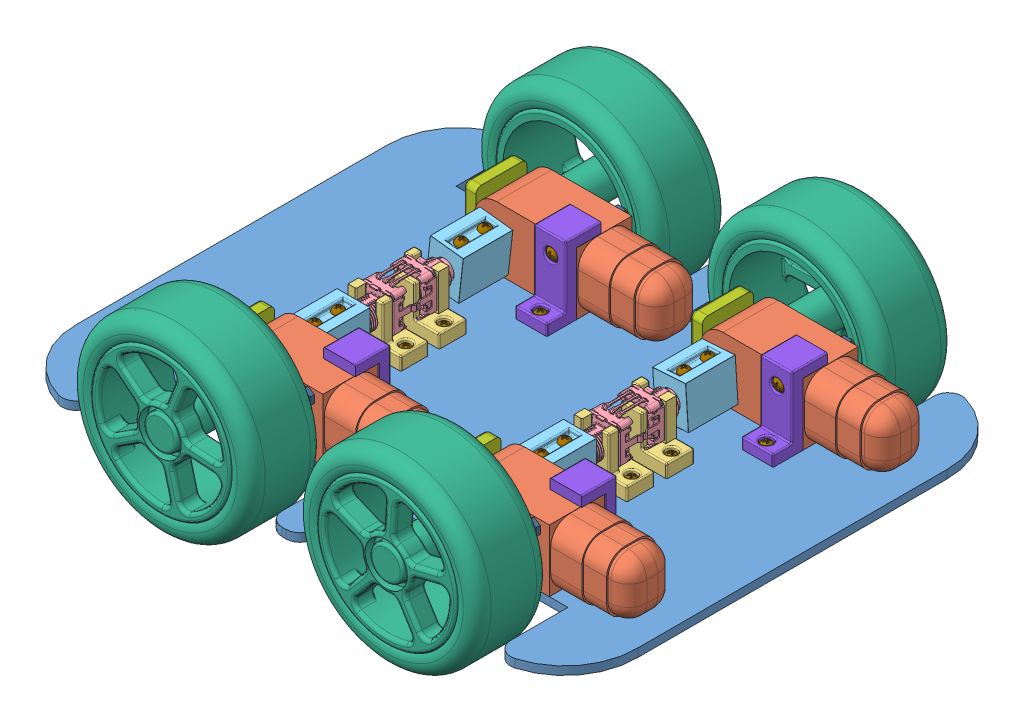
SolidWorks assembly RC Car v2, configuration Default. Lengths in mm.
Overall size (203.21 85.5 173.15).
81 component instances, 10 part files, 181 mates.
Components (placement in the parent):
- Chassis_v1-1: Chassis_v1 [Default] at (-89.4003 13.7937 36.785) size (203.21 3 165.1)
- Motor_v1-3: Motor_v1 [Default] at (-138.9213 39.2937 -19.165) x (1 0 0) z (0 -1 0) size (69.42 36.34 22.5)
- Motor_v1-4: Motor_v1 [Default] at (-138.9213 16.7937 92.735) x (1 0 0) z (0 1 0) size (69.42 36.34 22.5)
- EncoderMount-1: EncoderMount [Default] at (-136.5617 16.7937 48.995) x (0 0 -1) z (1 0 0) size (10 17.94 25.6)
- EncoderMount-2: EncoderMount [Default] at (-123.9617 16.7937 25.075) x (0 0 1) z (-1 0 0) size (10 17.94 25.6)
- Encoder-2: Encoder [Default] at (-130.3117 28.0463 39.685) x (-1 0 0) z (0 0 1) size (14 14.25 28.55)
- Shaft-Encoder-Hub-1: Shaft-Encoder-Hub [Default] at (-130.3117 20.5463 62.235) x (1 0 0) z (0 1 0) size (12 18 15)
- Shaft-Encoder-Hub-2: Shaft-Encoder-Hub [Default] at (-131.1485 20.5879 11.335) x (-0.993756 0.111573 0) z (0.111573 0.993756 0) size (12 18 15)
- Wheel_v2-1: Wheel_v2 [Default] at (-130.3117 28.0463 123.3598) x (0.931323 -0.364194 0) z (0.364194 0.931323 0) size (66 29.12 66)
- Wheel_v2-2: Wheel_v2 [Default] at (-130.3117 28.0411 -49.7897) x (-0.948699 0.31618 0) z (0.31618 0.948699 0) size (66 29.12 66)
- Motor_v1-5: Motor_v1 [Default] at (-56.9152 39.2937 -19.1649) x (1 0 -0.000002) z (0 -1 0) size (69.42 36.34 22.5)
- Motor_v1-6: Motor_v1 [Default] at (-56.9152 16.7937 92.7351) x (1 0 -0.000002) z (0 1 0) size (69.42 36.34 22.5)
- EncoderMount-3: EncoderMount [Default] at (-42.0557 16.7937 24.5751) x (0.000002 0 1) z (-1 0 0.000002) size (10 17.94 25.6)
- EncoderMount-4: EncoderMount [Default] at (-54.6556 16.7937 48.995) x (-0.000002 0 -1) z (1 0 -0.000002) size (10 17.94 25.6)
- Wheel_v2-3: Wheel_v2 [Default] at (-48.4153 28.0437 -49.7896) x (0.960777 -0.277321 -0.000002) z (-0.277321 -0.960777 0.000001) size (66 29.12 66)
- Wheel_v2-4: Wheel_v2 [Default] at (-48.4152 28.0437 123.3598) x (0.997475 -0.071022 -0.000002) z (0.071022 0.997475 0) size (66 29.12 66)
- DCMotorMountRear-1: DCMotorMountRear [Default] at (-56.9153 16.7937 73.2501) x (0 1 0) z (1 0 -0.000002) size (22.45 18.5 11.23)
- DCMotorMountSide-1: DCMotorMountSide [Default] at (-31.4152 43.0337 4.8351) x (0 -1 0) z (0.000002 0 1) size (26.24 11.5 19.6)
- DCMotorMountRear-2: DCMotorMountRear [Default] at (-56.9152 16.7937 -18.1799) x (0 1 0) z (1 0 -0.000002) size (22.45 18.5 11.23)
- DCMotorMountSide-2: DCMotorMountSide [Default] at (-19.4153 43.0337 68.735) x (0 -1 0) z (-0.000002 0 -1) size (26.24 11.5 19.6)
- DCMotorMountSide-3: DCMotorMountSide [Default] at (-113.4213 43.0337 4.835) x (0 -1 0) z (0 0 1) size (26.24 11.5 19.6)
- DCMotorMountRear-3: DCMotorMountRear [Default] at (-138.9213 16.7937 73.25) x (0 1 0) z (1 0 0) size (22.45 18.5 11.23)
- DCMotorMountRear-4: DCMotorMountRear [Default] at (-138.9213 16.7937 -18.18) x (0 1 0) z (1 0 0) size (22.45 18.5 11.23)
- Encoder-3: Encoder [Default] at (-48.3056 28.0463 39.685) x (-1 0 0.000002) z (0.000002 0 1) size (14 14.25 28.55)
- Shaft-Encoder-Hub-3: Shaft-Encoder-Hub [Default] at (-48.3056 20.5463 62.235) x (1 0 -0.000002) z (0 1 0) size (12 18 15)
- Shaft-Encoder-Hub-5: Shaft-Encoder-Hub [Default] at (-47.9011 20.5613 11.3351) x (-0.997648 -0.068548 0.000002) z (-0.068548 0.997648 0) size (12 18 15)
- Encoder-4: Encoder [Default] at (-130.3117 28.0411 34.385) x (1 0 0) z (0 0 -1) size (14 14.25 28.55)
- Encoder-5: Encoder [Default] at (-48.4151 28.0437 33.8851) x (1 0 -0.000002) z (-0.000002 0 -1) size (14 14.25 28.55)
- DCMotorMountSide-4: DCMotorMountSide [Default] at (-101.4213 43.0337 68.735) x (0 -1 0) z (0 0 -1) size (26.24 11.5 19.6)
- round head screw_ai-1: round head screw_ai [CR-RHMS 0.086-56x0.3125x0.3125-N] at (-146.7486 20.7963 -8.93) x (0 -1 0) z (-0.489192 0 0.872176) size (9.64 4.11 4.11)
- round head screw_ai-4: round head screw_ai [CR-RHMS 0.086-64x0.125x0.125-N] at (-130.3431 35.8061 67.235) x (0 -1 0) z (0 0 1) size (4.88 4.11 4.11)
- round head screw_ai-5: round head screw_ai [CR-RHMS 0.086-64x0.125x0.125-N] at (-130.3431 35.8061 58.685) x (0 -1 0) z (0 0 1) size (4.88 4.11 4.11)
- round head screw_ai-8: round head screw_ai [CR-RHMS 0.086-64x0.3125x0.3125-N] at (-120.7217 21.2663 30.075) x (0 -1 0) z (0 0 1) size (9.64 4.11 4.11)
- round head screw_ai-9: round head screw_ai [CR-RHMS 0.086-64x0.3125x0.3125-N] at (-120.7172 21.2663 43.995) x (0 -1 0) z (0 0 1) size (9.64 4.11 4.11)
- round head screw_ai-12: round head screw_ai [CR-RHMS 0.086-64x0.125x0.125-N] at (-129.4146 35.749 14.885) x (-0.111573 -0.993756 0) z (0 0 1) size (4.88 4.11 4.11)
- round head screw_ai-13: round head screw_ai [CR-RHMS 0.086-64x0.125x0.125-N] at (-129.4146 35.749 6.335) x (-0.111573 -0.993756 0) z (0 0 1) size (4.88 4.11 4.11)
- round head screw_ai-16: round head screw_ai [CR-RHMS 0.086-64x0.125x0.125-N] at (-48.9157 35.7874 14.8851) x (0.068548 -0.997648 0) z (0 0 1) size (4.88 4.11 4.11)
- round head screw_ai-17: round head screw_ai [CR-RHMS 0.086-64x0.125x0.125-N] at (-48.9157 35.7874 6.3351) x (0.068548 -0.997648 0) z (0 0 1) size (4.88 4.11 4.11)
- round head screw_ai-22: round head screw_ai [CR-RHMS 0.086-64x0.3125x0.3125-N] at (-38.8157 21.2663 29.5751) x (0 -1 0) z (-0.864943 0 -0.501871) size (9.64 4.11 4.11)
- round head screw_ai-23: round head screw_ai [CR-RHMS 0.086-64x0.3125x0.3125-N] at (-38.8112 21.2663 43.995) x (0 -1 0) z (0.820937 0 -0.571019) size (9.64 4.11 4.11)
- round head screw_ai-24: round head screw_ai [CR-RHMS 0.086-64x0.3125x0.3125-N] at (-57.9001 21.2663 29.5751) x (0 -1 0) z (0.891318 0 -0.453379) size (9.64 4.11 4.11)
- round head screw_ai-25: round head screw_ai [CR-RHMS 0.086-64x0.3125x0.3125-N] at (-57.8956 21.2663 43.9951) x (0 -1 0) z (0.010277 0 -0.999947) size (9.64 4.11 4.11)
- round head screw_ai-26: round head screw_ai [CR-RHMS 0.086-64x0.125x0.125-N] at (-48.3371 35.8061 58.685) x (0 -1 0) z (0 0 1) size (4.88 4.11 4.11)
- round head screw_ai-27: round head screw_ai [CR-RHMS 0.086-64x0.125x0.125-N] at (-48.3371 35.8061 67.235) x (0 -1 0) z (0 0 1) size (4.88 4.11 4.11)
- round head screw_ai-28: round head screw_ai [CR-RHMS 0.086-64x0.3125x0.3125-N] at (-25.1653 20.7963 65.335) x (0 -1 0) z (0 0 1) size (9.64 4.11 4.11)
- round head screw_ai-30: round head screw_ai [CR-RHMS 0.086-64x0.3125x0.3125-N] at (-64.7425 20.7963 82.5001) x (0 -1 0) z (0 0 1) size (9.64 4.11 4.11)
- round head screw_ai-32: round head screw_ai [CR-RHMS 0.086-64x0.3125x0.3125-N] at (-25.6652 20.7963 8.2351) x (0 -1 0) z (0.8593 0 0.511472) size (9.64 4.11 4.11)
- round head screw_ai-34: round head screw_ai [CR-RHMS 0.086-64x0.3125x0.3125-N] at (-139.8017 21.2663 43.995) x (0 -1 0) z (0.862694 0 -0.505726) size (9.64 4.11 4.11)
- round head screw_ai-35: round head screw_ai [CR-RHMS 0.086-64x0.3125x0.3125-N] at (-139.8061 21.2663 30.075) x (0 -1 0) z (0.883954 0 -0.467575) size (9.64 4.11 4.11)
- round head screw_ai-41: round head screw_ai [CR-RHMS 0.086-64x0.3125x0.3125-N] at (-146.7486 20.7963 82.5) x (0 -1 0) z (0 0 1) size (9.64 4.11 4.11)
- round head screw_ai-43: round head screw_ai [CR-RHMS 0.086-64x0.3125x0.3125-N] at (-107.6713 20.7963 8.235) x (0 -1 0) z (0 0 1) size (9.64 4.11 4.11)
- round head screw_ai-45: round head screw_ai [CR-RHMS 0.086-64x0.3125x0.3125-N] at (-64.7424 20.7963 -8.9299) x (0 -1 0) z (0.853062 0 0.52181) size (9.64 4.11 4.11)
- round head screw_ai-49: round head screw_ai [CR-RHMS 0.086-64x0.3125x0.3125-N] at (-107.1713 20.7963 65.335) x (0 -1 0) z (0 0 1) size (9.64 4.11 4.11)
- machine screw nut hex_ai-3: machine screw nut hex_ai [MSHXNUT 0.086-56-S-N] at (-120.7217 12.1173 30.075) x (0.837169 0 0.546944) z (0 -1 0) size (4.78 5.51 1.68)
- machine screw nut hex_ai-4: machine screw nut hex_ai [MSHXNUT 0.086-56-S-N] at (-139.8017 12.1173 43.995) x (0.890955 0 0.454091) z (0 -1 0) size (4.78 5.51 1.68)
- machine screw nut hex_ai-5: machine screw nut hex_ai [MSHXNUT 0.086-56-S-N] at (-120.7172 12.1173 43.995) x (0.837169 0 0.546944) z (0 -1 0) size (4.78 5.51 1.68)
- machine screw nut hex_ai-6: machine screw nut hex_ai [MSHXNUT 0.086-56-S-N] at (-146.7486 13.9311 82.5) x (1 0 0) z (0 1 0) size (4.78 5.51 1.68)
- machine screw nut hex_ai-7: machine screw nut hex_ai [MSHXNUT 0.086-56-S-N] at (-107.1713 12.1173 65.335) x (0.833725 0 0.552179) z (0 -1 0) size (4.78 5.51 1.68)
- machine screw nut hex_ai-8: machine screw nut hex_ai [MSHXNUT 0.086-56-S-N] at (-57.9001 12.1173 29.5751) x (0.837169 0 0.546944) z (0 -1 0) size (4.78 5.51 1.68)
- machine screw nut hex_ai-10: machine screw nut hex_ai [MSHXNUT 0.086-56-S-N] at (-38.8157 12.1173 29.5751) x (0.837169 0 0.546944) z (0 -1 0) size (4.78 5.51 1.68)
- machine screw nut hex_ai-12: machine screw nut hex_ai [MSHXNUT 0.086-56-S-N] at (-57.8956 12.1173 43.9951) x (0.837169 0 0.546944) z (0 -1 0) size (4.78 5.51 1.68)
- machine screw nut hex_ai-13: machine screw nut hex_ai [MSHXNUT 0.086-56-S-N] at (-25.6652 12.1173 8.2351) x (0.837169 0 0.546944) z (0 -1 0) size (4.78 5.51 1.68)
- machine screw nut hex_ai-14: machine screw nut hex_ai [MSHXNUT 0.086-56-S-N] at (-38.8112 12.1173 43.995) x (0.837169 0 0.546944) z (0 -1 0) size (4.78 5.51 1.68)
- machine screw nut hex_ai-15: machine screw nut hex_ai [MSHXNUT 0.086-56-S-N] at (-64.7425 12.1173 82.5001) x (0.837169 0 0.546944) z (0 -1 0) size (4.78 5.51 1.68)
- machine screw nut hex_ai-16: machine screw nut hex_ai [MSHXNUT 0.086-56-S-N] at (-25.1653 12.1173 65.335) x (0.837169 0 0.546944) z (0 -1 0) size (4.78 5.51 1.68)
- machine screw nut hex_ai-17: machine screw nut hex_ai [MSHXNUT 0.086-56-S-N] at (-64.7424 12.1173 -8.9299) x (0.837169 0 0.546944) z (0 -1 0) size (4.78 5.51 1.68)
- machine screw nut hex_ai-19: machine screw nut hex_ai [MSHXNUT 0.086-64-S-N] at (-107.6713 12.1173 8.235) x (0.837169 0 0.546944) z (0 -1 0) size (4.78 5.51 1.68)
- machine screw nut hex_ai-20: machine screw nut hex_ai [MSHXNUT 0.086-56-S-N] at (-146.7486 12.1173 -8.93) x (0.814768 0 0.579788) z (0 -1 0) size (4.78 5.51 1.68)
- machine screw nut hex_ai-21: machine screw nut hex_ai [MSHXNUT 0.086-56-S-N] at (-139.8061 12.1173 30.075) x (0.853088 0 0.521767) z (0 -1 0) size (4.78 5.51 1.68)
- round head screw_ai-55: round head screw_ai [CR-RHMS 0.099-56x1x1-N] at (-25.4152 36.2937 5.3163) x (-0.000002 0 -1) z (-0.335837 -0.94192 0.000001) size (27.33 4.75 4.75)
- round head screw_ai-56: round head screw_ai [CR-RHMS 0.099-56x1x1-N] at (-25.4153 36.2937 68.2538) x (0.000002 0 1) z (-1 0 0.000002) size (27.33 4.75 4.75)
- round head screw_ai-57: round head screw_ai [CR-RHMS 0.099-56x1x1-N] at (-107.4213 36.2937 68.2538) x (0 0 1) z (-1 0 0) size (27.33 4.75 4.75)
- machine screw nut hex_ai-24: machine screw nut hex_ai [MSHXNUT 0.099-56-S-N] at (-107.4213 36.2937 99.1981) x (-0.923728 -0.383049 0) z (0 0 -1) size (4.78 5.51 1.68)
- machine screw nut hex_ai-25: machine screw nut hex_ai [MSHXNUT 0.099-56-S-N] at (-25.4152 36.2937 -25.8056) x (1 0 -0.000002) z (0.000002 0 1) size (4.78 5.51 1.68)
- machine screw nut hex_ai-26: machine screw nut hex_ai [MSHXNUT 0.099-56-S-N] at (-25.4152 36.2937 99.2067) x (-0.923728 -0.383049 0.000002) z (-0.000002 0 -1) size (4.78 5.51 1.68)
- round head screw_ai-58: round head screw_ai [CR-RHMS 0.099-56x1x1-N] at (-107.4213 36.2937 5.3162) x (0 0 -1) z (0.007756 0.99997 0) size (27.33 4.75 4.75)
- machine screw nut hex_ai-28: machine screw nut hex_ai [MSHXNUT 0.099-56-S-N] at (-107.4213 36.2937 -25.7103) size (4.78 5.51 1.68)
- machine screw nut hex_ai-29: machine screw nut hex_ai [MSHXNUT 0.099-56-S-N] at (-25.4152 36.2937 -20.8413) x (0.923728 0.383049 -0.000002) z (-0.000002 0 -1) size (4.78 5.51 1.68)
- machine screw nut hex_ai-30: machine screw nut hex_ai [MSHXNUT 0.099-56-S-N] at (-107.4213 36.2937 -20.8414) x (0.923728 0.383049 0) z (0 0 -1) size (4.78 5.51 1.68)
- machine screw nut hex_ai-31: machine screw nut hex_ai [MSHXNUT 0.099-56-S-N] at (-107.4213 36.2937 94.4114) x (-1 0 0) z (0 0 1) size (4.78 5.51 1.68)
- machine screw nut hex_ai-32: machine screw nut hex_ai [MSHXNUT 0.099-56-S-N] at (-25.4152 36.2937 94.5433) x (-0.999996 0.002881 0.000002) z (0.000002 0 1) size (4.78 5.51 1.68)
Mates (geometry in assembly coordinates):
- Coincident2: coincident anti-aligned: plane of Chassis_v1-1 through (-165.0003 16.7937 -19.765) normal (0 1 0); plane of Motor_v1-3 through (-138.9213 16.7937 0.835) normal (0 -1 0)
- Coincident5: coincident anti-aligned: plane of Chassis_v1-1 through (-165.0003 16.7937 -19.765) normal (0 1 0); plane of Motor_v1-4 through (-138.9213 16.7937 72.735) normal (0 -1 0)
- Parallel3: parallel anti-aligned: plane of Motor_v1-3 through (-130.3117 28.0411 8.235) normal (0 0 1); plane of Motor_v1-4 through (-130.3117 28.0463 65.335) normal (0 0 -1)
- Coincident7: coincident anti-aligned: plane of Chassis_v1-1 through (-165.0003 16.7937 -19.765) normal (0 1 0); plane of EncoderMount-1 through (-123.9617 16.7937 38.995) normal (0 -1 0)
- Parallel4: parallel anti-aligned: plane of Motor_v1-4 through (-138.9213 16.7937 72.735) normal (0 0 -1); plane of EncoderMount-1 through (-123.9617 16.7937 48.995) normal (0 0 1)
- Parallel5: parallel: plane of Chassis_v1-1 through (-165.6003 16.7937 92.735) normal (0 0 1); line of Motor_v1-4 through (-138.9213 28.0437 72.735) axis (1 0 0)
- Coincident11: coincident aligned: plane of Chassis_v1-1 through (-165.6003 16.7937 92.735) normal (0 0 1); plane of Motor_v1-4 through (-138.9213 16.7937 92.735) normal (0 0 1)
- Coincident16: coincident: moEndPointRef_w of Chassis_v1-1; line of Motor_v1-4 through (-130.4213 39.2937 92.735) axis (0 -1 0)
- Coincident19: coincident: moEndPointRef_w of Chassis_v1-1; line of Motor_v1-3 through (-130.4213 16.7937 -19.165) axis (0 1 0)
- Coincident22: coincident anti-aligned: plane of Chassis_v1-1 through (-165.0003 16.7937 -19.765) normal (0 1 0); plane of EncoderMount-2 through (-136.5617 16.7937 35.075) normal (0 -1 0)
- Parallel10: parallel anti-aligned: plane of Motor_v1-3 through (-138.9213 39.2937 0.835) normal (0 0 1); plane of EncoderMount-2 through (-136.5617 16.7937 25.075) normal (0 0 -1)
- Parallel19: parallel anti-aligned: plane of Motor_v1-4 through (-138.9213 16.7937 72.735) normal (0 0 -1); plane of Shaft-Encoder-Hub-1 through (-136.3117 35.5463 71.235) normal (0 0 1)
- Parallel20: parallel anti-aligned: plane of Motor_v1-3 through (-138.9213 39.2937 0.835) normal (0 0 1); plane of Shaft-Encoder-Hub-2 through (-123.5123 34.8248 2.335) normal (0 0 -1)
- Concentric2: concentric aligned: cylinder of Motor_v1-4 through (-130.3117 28.0463 65.335) axis (0 0 1) radius 2.7328; cylinder of Shaft-Encoder-Hub-1 through (-130.3117 28.0463 53.235) axis (0 0 1) radius 3.5
- Concentric5: concentric aligned: cylinder of Motor_v1-3 through (-130.3117 28.0411 8.235) axis (0 0 -1) radius 2.7328; cylinder of Shaft-Encoder-Hub-2 through (-130.3117 28.0411 20.335) axis (0 0 -1) radius 3.5
- Distance4: distance = 1.5 mm anti-aligned: plane of Shaft-Encoder-Hub-2 through (-123.5123 34.8248 2.335) normal (0 0 -1); plane of Motor_v1-3 through (-138.9213 39.2937 0.835) normal (0 0 1)
- Distance5: distance = 1.5 mm anti-aligned: plane of Motor_v1-4 through (-138.9213 16.7937 72.735) normal (0 0 -1); plane of Shaft-Encoder-Hub-1 through (-136.3117 35.5463 71.235) normal (0 0 1)
- Concentric6: concentric anti-aligned: cylinder of Encoder-2 through (-130.3117 28.0463 47.8056) axis (0 0 -1) radius 3; cylinder of Shaft-Encoder-Hub-1 through (-130.3117 28.0463 53.235) axis (0 0 1) radius 3.5
- Distance6: distance = 1 mm anti-aligned: plane of Encoder-2 through (-130.3117 24.0463 52.235) normal (0 0 1); plane of Shaft-Encoder-Hub-1 through (-136.3117 35.5463 53.235) normal (0 0 -1)
- Parallel24: parallel aligned: plane of Chassis_v1-1 through (-165.0003 16.7937 -19.765) normal (0 1 0); plane of Encoder-2 through (-127.9673 32.0463 39.926) normal (0 1 0)
- Coincident46: coincident anti-aligned: plane of EncoderMount-1 through (-123.9617 21.5137 41.185) normal (0 0 1); plane of Encoder-2 through (-126.1117 33.1463 41.185) normal (0 0 -1)
- Parallel25: parallel aligned: plane of EncoderMount-1 through (-136.5617 16.7937 48.995) normal (-1 0 0); plane of Shaft-Encoder-Hub-1 through (-136.3117 35.5463 53.235) normal (-1 0 0)
- Parallel27: parallel aligned: line of EncoderMount-1 through (-130.2617 32.9137 38.995) axis (0 -1 0); line of Shaft-Encoder-Hub-1 through (-130.3117 35.4963 53.235) axis (0 -1 0)
- Concentric8: concentric anti-aligned: cylinder of Motor_v1-4 through (-130.3117 28.0463 65.335) axis (0 0 1) radius 2.7328; cylinder of Wheel_v2-1 through (-130.3117 28.0463 114.0957) axis (0 0 -1) radius 1.675
- Distance11: distance = 1.5 mm anti-aligned: plane of Motor_v1-4 through (-138.9213 16.7937 92.735) normal (0 0 1); plane of Wheel_v2-1 through (-128.7517 27.4362 94.235) normal (0 0 -1)
- Concentric9: concentric anti-aligned: cylinder of Motor_v1-3 through (-130.3117 28.0411 8.235) axis (0 0 -1) radius 2.7328; circle of Wheel_v2-2
- Distance13: distance = 1.5 mm anti-aligned: plane of Wheel_v2-2 through (-131.9007 28.5707 -20.665) normal (0 0 1); plane of Motor_v1-3 through (-138.9213 39.2937 -19.165) normal (0 0 -1)
- Coincident66: coincident anti-aligned: plane of Chassis_v1-1 through (-165.0003 16.7937 -19.765) normal (0 1 0); plane of Motor_v1-6 through (-56.9153 16.7937 72.7351) normal (0 -1 0)
- Coincident69: coincident anti-aligned: plane of Chassis_v1-1 through (-165.0003 16.7937 -19.765) normal (0 1 0); plane of Motor_v1-5 through (-56.9152 16.7937 0.8351) normal (0 -1 0)
- Coincident70: coincident aligned: plane of Chassis_v1-1 through (-13.2003 16.7937 -19.165) normal (-0.000002 0 -1); plane of Motor_v1-5 through (-56.9152 39.2937 -19.1649) normal (-0.000002 0 -1)
- Coincident71: coincident: moEndPointRef_w of Chassis_v1-1; line of Motor_v1-5 through (-48.4152 16.7937 -19.1649) axis (0 1 0)
- Concentric10: concentric anti-aligned: cylinder of Motor_v1-5 through (-48.4152 28.0437 8.2351) axis (-0.000002 0 -1) radius 2.6721; cylinder of Wheel_v2-3 through (-48.4153 28.0437 -40.5255) axis (0.000002 0 1) radius 1.675
- Distance14: distance = 1.5 mm anti-aligned: plane of Motor_v1-5 through (-56.9152 39.2937 -19.1649) normal (-0.000002 0 -1); plane of Wheel_v2-3 through (-46.8059 27.5792 -20.6649) normal (0.000002 0 1)
- Concentric11: concentric anti-aligned: cylinder of Motor_v1-6 through (-48.4153 28.0437 65.335) axis (0.000002 0 1) radius 2.6721; cylinder of Wheel_v2-4 through (-48.4152 28.0437 114.0957) axis (-0.000002 0 -1) radius 1.675
- Distance15: distance = 1.5 mm anti-aligned: plane of Motor_v1-6 through (-56.9152 16.7937 92.7351) normal (0.000002 0 1); plane of Wheel_v2-4 through (-46.7445 27.9247 94.235) normal (-0.000002 0 -1)
- Parallel29: parallel anti-aligned: plane of Motor_v1-6 through (-56.9153 16.7937 72.7351) normal (-0.000002 0 -1); plane of EncoderMount-4 through (-42.0556 16.7937 48.995) normal (0.000002 0 1)
- Parallel30: parallel anti-aligned: plane of Motor_v1-5 through (-56.9152 39.2937 0.8351) normal (0.000002 0 1); plane of EncoderMount-3 through (-54.6557 16.7937 24.5751) normal (-0.000002 0 -1)
- Coincident81: coincident aligned: line of EncoderMount-1 through (-142.5617 21.5137 39.495) axis (0 0 1); line of EncoderMount-2 through (-142.5617 21.5137 25.575) axis (0 0 1)
- Coincident82: coincident aligned: line of EncoderMount-3 through (-60.6557 21.5137 25.0751) axis (0.000002 0 1); line of EncoderMount-4 through (-60.6556 21.5137 39.4951) axis (0.000002 0 1)
- Coincident83: coincident anti-aligned: plane of Chassis_v1-1 through (-165.0003 16.7937 -19.765) normal (0 1 0); plane of DCMotorMountRear-1 through (-56.9152 16.7937 91.7501) normal (0 -1 0)
- Coincident86: coincident anti-aligned: plane of Motor_v1-6 through (-56.9153 16.7937 72.7351) normal (-1 0 0.000002); plane of DCMotorMountRear-1 through (-56.9152 39.2437 91.7501) normal (1 0 -0.000002)
- Coincident87: coincident anti-aligned: plane of Motor_v1-6 through (-62.0452 25.4787 84.1501) normal (0.000002 0 1); plane of DCMotorMountRear-1 through (-61.4152 24.7937 84.1501) normal (-0.000002 0 -1)
- Coincident88: coincident anti-aligned: plane of Chassis_v1-1 through (-165.0003 16.7937 -19.765) normal (0 1 0); plane of DCMotorMountSide-1 through (-19.9152 16.7937 0.835) normal (0 -1 0)
- Coincident92: coincident anti-aligned: plane of Motor_v1-5 through (-56.9152 39.2937 0.8351) normal (0.000002 0 1); plane of DCMotorMountSide-1 through (-19.9152 39.3937 0.835) normal (-0.000002 0 -1)
- Coincident93: coincident anti-aligned: plane of Chassis_v1-1 through (-165.0003 16.7937 -19.765) normal (0 1 0); plane of DCMotorMountRear-2 through (-56.9152 16.7937 0.3201) normal (0 -1 0)
- Coincident94: coincident anti-aligned: plane of Motor_v1-5 through (-56.9152 39.2937 0.8351) normal (-1 0 0.000002); plane of DCMotorMountRear-2 through (-56.9152 39.2437 0.3201) normal (1 0 -0.000002)
- Coincident95: coincident anti-aligned: plane of Motor_v1-5 through (-62.0452 30.6087 -10.5799) normal (-0.000002 0 -1); plane of DCMotorMountRear-2 through (-61.4152 31.2437 -10.5799) normal (0.000002 0 1)
- Coincident96: coincident anti-aligned: plane of Chassis_v1-1 through (-165.0003 16.7937 -19.765) normal (0 1 0); plane of DCMotorMountSide-2 through (-30.9153 16.7937 72.735) normal (0 -1 0)
- Coincident99: coincident anti-aligned: plane of Chassis_v1-1 through (-165.0003 16.7937 -19.765) normal (0 1 0); plane of DCMotorMountSide-3 through (-101.9213 16.7937 0.835) normal (0 -1 0)
- Coincident100: coincident anti-aligned: plane of Motor_v1-3 through (-138.9213 39.2937 0.835) normal (0 0 1); plane of DCMotorMountSide-3 through (-101.9213 39.3937 0.835) normal (0 0 -1)
- Coincident101: coincident anti-aligned: plane of Chassis_v1-1 through (-165.0003 16.7937 -19.765) normal (0 1 0); plane of DCMotorMountRear-3 through (-138.9213 16.7937 91.75) normal (0 -1 0)
- Coincident102: coincident anti-aligned: plane of Motor_v1-4 through (-138.9213 16.7937 72.735) normal (-1 0 0); plane of DCMotorMountRear-3 through (-138.9213 39.2437 91.75) normal (1 0 0)
- Coincident103: coincident anti-aligned: plane of Motor_v1-4 through (-144.0513 25.4787 84.15) normal (0 0 1); plane of DCMotorMountRear-3 through (-143.4213 24.7937 84.15) normal (0 0 -1)
- Coincident104: coincident anti-aligned: plane of Chassis_v1-1 through (-165.0003 16.7937 -19.765) normal (0 1 0); plane of DCMotorMountRear-4 through (-138.9213 16.7937 0.32) normal (0 -1 0)
- Coincident105: coincident anti-aligned: plane of Motor_v1-3 through (-138.9213 39.2937 0.835) normal (-1 0 0); plane of DCMotorMountRear-4 through (-138.9213 39.2437 0.32) normal (1 0 0)
- Coincident106: coincident anti-aligned: plane of Motor_v1-3 through (-144.0513 30.6087 -10.58) normal (0 0 -1); plane of DCMotorMountRear-4 through (-143.4213 31.2437 -10.58) normal (0 0 1)
- Distance16: distance = 1.5 mm anti-aligned: plane of Motor_v1-6 through (-56.9153 16.7937 72.7351) normal (-0.000002 0 -1); plane of Shaft-Encoder-Hub-3 through (-54.3056 35.5463 71.235) normal (0.000002 0 1)
- Concentric18: concentric aligned: cylinder of Motor_v1-6 through (-48.3056 28.0463 65.335) axis (0.000002 0 1) radius 2.7328; circle of Shaft-Encoder-Hub-3
- Concentric19: concentric anti-aligned: cylinder of Encoder-3 through (-48.3056 28.0463 47.8056) axis (-0.000002 0 -1) radius 3; cylinder of Shaft-Encoder-Hub-3 through (-48.3056 28.0463 53.235) axis (0.000002 0 1) radius 3.5
- Distance17: distance = 1 mm anti-aligned: plane of Encoder-3 through (-48.3056 24.0463 52.235) normal (0.000002 0 1); plane of Shaft-Encoder-Hub-3 through (-54.3056 35.5463 53.235) normal (-0.000002 0 -1)
- Coincident110: coincident anti-aligned: plane of Chassis_v1-1 through (-165.0003 16.7937 -19.765) normal (0 1 0); plane of EncoderMount-3 through (-54.6557 16.7937 34.5751) normal (0 -1 0)
- Coincident112: coincident anti-aligned: plane of Chassis_v1-1 through (-165.0003 16.7937 -19.765) normal (0 1 0); plane of EncoderMount-4 through (-42.0557 16.7937 38.995) normal (0 -1 0)
- Coincident113: coincident anti-aligned: plane of EncoderMount-4 through (-42.0556 21.5137 41.185) normal (0.000002 0 1); plane of Encoder-3 through (-44.1056 33.1463 41.185) normal (-0.000002 0 -1)
- Coincident116: coincident anti-aligned: plane of EncoderMount-4 through (-44.4556 16.7937 41.855) normal (1 0 -0.000002); plane of Encoder-3 through (-44.4556 22.1463 39.685) normal (-1 0 0.000002)
- Distance20: distance = 1.5 mm anti-aligned: plane of Motor_v1-5 through (-56.9152 39.2937 0.8351) normal (0.000002 0 1); plane of Shaft-Encoder-Hub-5 through (-42.9434 35.9373 2.3351) normal (-0.000002 0 -1)
- Concentric20: concentric aligned: cylinder of Motor_v1-5 through (-48.4152 28.0437 8.2351) axis (-0.000002 0 -1) radius 2.6721; cylinder of Shaft-Encoder-Hub-5 through (-48.4151 28.0437 20.3351) axis (-0.000002 0 -1) radius 3.5
- Coincident118: coincident anti-aligned: plane of EncoderMount-1 through (-134.1617 16.7937 41.855) normal (-1 0 0); plane of Encoder-2 through (-134.1617 22.1463 39.685) normal (1 0 0)
- Coincident119: coincident anti-aligned: plane of Motor_v1-6 through (-56.9153 16.7937 72.7351) normal (-0.000002 0 -1); plane of DCMotorMountSide-2 through (-30.9153 39.3937 72.735) normal (0.000002 0 1)
- Concentric21: concentric anti-aligned: cylinder of Shaft-Encoder-Hub-2 through (-130.3117 28.0411 20.335) axis (0 0 -1) radius 3.5; cylinder of Encoder-4 through (-130.3117 28.0411 26.2645) axis (0 0 1) radius 3
- Distance21: distance = 1.5 mm anti-aligned: plane of Encoder-4 through (-130.3117 24.0411 21.835) normal (0 0 -1); plane of Shaft-Encoder-Hub-2 through (-123.5123 34.8248 20.335) normal (0 0 1)
- Coincident122: coincident anti-aligned: plane of EncoderMount-2 through (-136.5617 21.5137 32.885) normal (0 0 -1); plane of Encoder-4 through (-134.5117 33.1411 32.885) normal (0 0 1)
- Parallel44: parallel anti-aligned: plane of EncoderMount-2 through (-126.3617 16.7937 32.215) normal (1 0 0); plane of Encoder-4 through (-126.4617 22.1411 34.385) normal (-1 0 0)
- Concentric22: concentric anti-aligned: cylinder of Shaft-Encoder-Hub-5 through (-48.4151 28.0437 20.3351) axis (-0.000002 0 -1) radius 3.5; cylinder of Encoder-5 through (-48.4151 28.0437 25.7646) axis (0.000002 0 1) radius 3
- Distance22: distance = 1 mm anti-aligned: plane of Encoder-5 through (-48.4151 24.0437 21.3351) normal (-0.000002 0 -1); plane of Shaft-Encoder-Hub-5 through (-42.9434 35.9373 20.3351) normal (0.000002 0 1)
- Coincident127: coincident anti-aligned: plane of EncoderMount-3 through (-54.6557 21.5137 32.3851) normal (-0.000002 0 -1); plane of Encoder-5 through (-52.6151 33.1437 32.3851) normal (0.000002 0 1)
- Parallel47: parallel anti-aligned: plane of EncoderMount-3 through (-52.2557 16.7937 31.7151) normal (-1 0 0.000002); plane of Encoder-5 through (-52.2651 22.1437 33.8851) normal (1 0 -0.000002)
- Coincident132: coincident anti-aligned: plane of Chassis_v1-1 through (-165.0003 16.7937 -19.765) normal (0 1 0); plane of DCMotorMountSide-4 through (-112.9213 16.7937 72.735) normal (0 -1 0)
- Coincident133: coincident anti-aligned: plane of Motor_v1-4 through (-138.9213 16.7937 72.735) normal (0 0 -1); plane of DCMotorMountSide-4 through (-112.9213 39.3937 72.735) normal (0 0 1)
- Concentric32: concentric aligned: cylinder of DCMotorMountRear-4 through (-146.7486 16.7437 -8.93) axis (0 1 0) radius 1.15; cylinder of round head screw_ai-1 through (-146.7486 20.7963 -8.93) axis (0 1 0) radius 1.0922
- Coincident143: coincident anti-aligned: circle of DCMotorMountRear-4; plane of round head screw_ai-1 through (-145.796 19.0437 -8.3957) normal (0 -1 0)
- Concentric33: concentric aligned: cylinder of Shaft-Encoder-Hub-1 through (-130.3431 31.0535 67.235) axis (0 1 0) radius 1.05; cylinder of round head screw_ai-4 through (-130.3431 35.8061 67.235) axis (0 1 0) radius 1.0922
- Coincident145: coincident anti-aligned: plane of Shaft-Encoder-Hub-1 through (-130.3117 34.0535 62.235) normal (0 1 0); plane of round head screw_ai-4 through (-129.2509 34.0535 67.235) normal (0 -1 0)
- Concentric34: concentric aligned: cylinder of Shaft-Encoder-Hub-1 through (-130.3431 31.0535 58.685) axis (0 1 0) radius 1.05; cylinder of round head screw_ai-5 through (-130.3431 35.8061 58.685) axis (0 1 0) radius 1.0922
- Coincident146: coincident anti-aligned: plane of Shaft-Encoder-Hub-1 through (-130.3117 34.0535 62.235) normal (0 1 0); plane of round head screw_ai-5 through (-129.2509 34.0535 58.685) normal (0 -1 0)
- Concentric37: concentric anti-aligned: cylinder of EncoderMount-2 through (-120.7217 19.7937 30.075) axis (0 -1 0) radius 1.25; cylinder of round head screw_ai-8 through (-120.7217 21.2663 30.075) axis (0 1 0) radius 1.0922
- Coincident149: coincident anti-aligned: plane of EncoderMount-2 through (-120.7217 19.5137 30.075) normal (0 1 0); plane of round head screw_ai-8 through (-119.6295 19.5137 30.075) normal (0 -1 0)
- Concentric38: concentric anti-aligned: cylinder of EncoderMount-1 through (-120.7172 19.7937 43.995) axis (0 -1 0) radius 1.25; cylinder of round head screw_ai-9 through (-120.7172 21.2663 43.995) axis (0 1 0) radius 1.0922
- Coincident150: coincident anti-aligned: plane of EncoderMount-1 through (-120.7172 19.5137 43.995) normal (0 1 0); plane of round head screw_ai-9 through (-119.625 19.5137 43.995) normal (0 -1 0)
- Concentric39: concentric aligned: cylinder of Shaft-Encoder-Hub-2 through (-129.9448 31.0261 14.885) axis (0.111573 0.993756 0) radius 1.05; cylinder of round head screw_ai-12 through (-129.4146 35.749 14.885) axis (0.111573 0.993756 0) radius 1.0922
- Coincident151: coincident anti-aligned: plane of Shaft-Encoder-Hub-2 through (-129.6414 34.0108 11.335) normal (0.111573 0.993756 0); plane of round head screw_ai-12 through (-128.5248 33.8855 14.885) normal (-0.111573 -0.993756 0)
- Concentric40: concentric aligned: cylinder of Shaft-Encoder-Hub-2 through (-129.9448 31.0261 6.335) axis (0.111573 0.993756 0) radius 1.05; cylinder of round head screw_ai-13 through (-129.4146 35.749 6.335) axis (0.111573 0.993756 0) radius 1.0922
- Coincident152: coincident anti-aligned: plane of Shaft-Encoder-Hub-2 through (-129.6414 34.0108 11.335) normal (0.111573 0.993756 0); plane of round head screw_ai-13 through (-128.5248 33.8855 6.335) normal (-0.111573 -0.993756 0)
- Concentric43: concentric aligned: cylinder of Shaft-Encoder-Hub-5 through (-48.5899 31.046 14.8851) axis (-0.068548 0.997648 0) radius 1.05; cylinder of round head screw_ai-16 through (-48.9157 35.7874 14.8851) axis (-0.068548 0.997648 0) radius 1.0922
- Coincident154: coincident anti-aligned: plane of Shaft-Encoder-Hub-5 through (-48.827 34.0368 11.3351) normal (-0.068548 0.997648 0); plane of round head screw_ai-16 through (-47.7059 34.1138 14.8851) normal (0.068548 -0.997648 0)
- Concentric44: concentric aligned: cylinder of Shaft-Encoder-Hub-5 through (-48.5899 31.046 6.3351) axis (-0.068548 0.997648 0) radius 1.05; cylinder of round head screw_ai-17 through (-48.9157 35.7874 6.3351) axis (-0.068548 0.997648 0) radius 1.0922
- Coincident155: coincident anti-aligned: plane of Shaft-Encoder-Hub-5 through (-48.827 34.0368 11.3351) normal (-0.068548 0.997648 0); plane of round head screw_ai-17 through (-47.7059 34.1138 6.3351) normal (0.068548 -0.997648 0)
- Concentric45: concentric anti-aligned: cylinder of EncoderMount-3 through (-38.8157 19.7937 29.5751) axis (0 -1 0) radius 1.25; cylinder of round head screw_ai-22 through (-38.8157 21.2663 29.5751) axis (0 1 0) radius 1.0922
- Coincident156: coincident anti-aligned: plane of EncoderMount-3 through (-38.8157 19.5137 29.5751) normal (0 1 0); plane of round head screw_ai-22 through (-39.3638 19.5137 30.5198) normal (0 -1 0)
- Concentric46: concentric anti-aligned: cylinder of EncoderMount-4 through (-38.8112 19.7937 43.995) axis (0 -1 0) radius 1.25; cylinder of round head screw_ai-23 through (-38.8112 21.2663 43.995) axis (0 1 0) radius 1.0922
- Coincident157: coincident anti-aligned: plane of EncoderMount-4 through (-38.8112 19.5137 43.995) normal (0 1 0); plane of round head screw_ai-23 through (-39.4349 19.5137 43.0984) normal (0 -1 0)
- Concentric47: concentric anti-aligned: cylinder of EncoderMount-3 through (-57.9001 19.7937 29.5751) axis (0 -1 0) radius 1.25; cylinder of round head screw_ai-24 through (-57.9001 21.2663 29.5751) axis (0 1 0) radius 1.0922
- Coincident158: coincident anti-aligned: plane of EncoderMount-3 through (-57.9001 19.5137 29.5751) normal (0 1 0); plane of round head screw_ai-24 through (-58.3953 19.5137 28.6016) normal (0 -1 0)
- Concentric48: concentric anti-aligned: cylinder of EncoderMount-4 through (-57.8956 19.7937 43.9951) axis (0 -1 0) radius 1.25; cylinder of round head screw_ai-25 through (-57.8956 21.2663 43.9951) axis (0 1 0) radius 1.0922
- Concentric49: concentric aligned: cylinder of Shaft-Encoder-Hub-3 through (-48.3371 31.0535 58.685) axis (0 1 0) radius 1.05; cylinder of round head screw_ai-26 through (-48.3371 35.8061 58.685) axis (0 1 0) radius 1.0922
- Coincident159: coincident anti-aligned: plane of Shaft-Encoder-Hub-3 through (-48.3056 34.0535 62.235) normal (0 1 0); plane of round head screw_ai-26 through (-47.2449 34.0535 58.685) normal (0 -1 0)
- Concentric50: concentric aligned: cylinder of Shaft-Encoder-Hub-3 through (-48.3371 31.0535 67.235) axis (0 1 0) radius 1.05; cylinder of round head screw_ai-27 through (-48.3371 35.8061 67.235) axis (0 1 0) radius 1.0922
- Coincident160: coincident anti-aligned: plane of Shaft-Encoder-Hub-3 through (-48.3056 34.0535 62.235) normal (0 1 0); plane of round head screw_ai-27 through (-47.2449 34.0535 67.235) normal (0 -1 0)
- Concentric51: concentric aligned: cylinder of DCMotorMountSide-2 through (-25.1653 16.5437 65.335) axis (0 1 0) radius 1.15; cylinder of round head screw_ai-28 through (-25.1653 20.7963 65.335) axis (0 1 0) radius 1.0922
- Coincident161: coincident anti-aligned: plane of DCMotorMountSide-2 through (-25.1653 19.0437 65.335) normal (0 1 0); plane of round head screw_ai-28 through (-24.0731 19.0437 65.335) normal (0 -1 0)
- Concentric53: concentric aligned: cylinder of DCMotorMountRear-1 through (-64.7425 16.7437 82.5001) axis (0 1 0) radius 1.15; cylinder of round head screw_ai-30 through (-64.7425 20.7963 82.5001) axis (0 1 0) radius 1.0922
- Coincident163: coincident anti-aligned: plane of DCMotorMountRear-1 through (-64.7425 19.0437 82.5001) normal (0 1 0); plane of round head screw_ai-30 through (-63.6503 19.0437 82.5001) normal (0 -1 0)
- Concentric55: concentric aligned: cylinder of DCMotorMountSide-1 through (-25.6652 16.5437 8.2351) axis (0 1 0) radius 1.15; cylinder of round head screw_ai-32 through (-25.6652 20.7963 8.2351) axis (0 1 0) radius 1.0922
- Coincident164: coincident anti-aligned: plane of DCMotorMountSide-1 through (-25.6652 19.0437 8.2351) normal (0 1 0); plane of round head screw_ai-32 through (-25.1065 19.0437 7.2965) normal (0 -1 0)
- Concentric57: concentric anti-aligned: cylinder of EncoderMount-1 through (-139.8017 19.7937 43.995) axis (0 -1 0) radius 1.25; cylinder of round head screw_ai-34 through (-139.8017 21.2663 43.995) axis (0 1 0) radius 1.0922
- Coincident166: coincident anti-aligned: plane of EncoderMount-1 through (-139.8017 19.5137 43.995) normal (0 1 0); plane of round head screw_ai-34 through (-140.354 19.5137 43.0528) normal (0 -1 0)
- Concentric58: concentric anti-aligned: cylinder of EncoderMount-2 through (-139.8061 19.7937 30.075) axis (0 -1 0) radius 1.25; cylinder of round head screw_ai-35 through (-139.8061 21.2663 30.075) axis (0 1 0) radius 1.0922
- Concentric59: concentric aligned: cylinder of DCMotorMountRear-3 through (-146.7486 16.7437 82.5) axis (0 1 0) radius 1.15; cylinder of round head screw_ai-41 through (-146.7486 20.7963 82.5) axis (0 1 0) radius 1.0922
- Coincident170: coincident anti-aligned: plane of DCMotorMountRear-3 through (-146.7486 19.0437 82.5) normal (0 1 0); plane of round head screw_ai-41 through (-145.6564 19.0437 82.5) normal (0 -1 0)
- Concentric61: concentric aligned: cylinder of DCMotorMountSide-3 through (-107.6713 16.5437 8.235) axis (0 1 0) radius 1.15; cylinder of round head screw_ai-43 through (-107.6713 20.7963 8.235) axis (0 1 0) radius 1.0922
- Coincident172: coincident anti-aligned: plane of DCMotorMountSide-3 through (-107.6713 19.0437 8.235) normal (0 1 0); plane of round head screw_ai-43 through (-106.5791 19.0437 8.235) normal (0 -1 0)
- Concentric62: concentric aligned: cylinder of DCMotorMountRear-2 through (-64.7424 16.7437 -8.9299) axis (0 1 0) radius 1.15; cylinder of round head screw_ai-45 through (-64.7424 20.7963 -8.9299) axis (0 1 0) radius 1.0922
- Coincident174: coincident anti-aligned: plane of DCMotorMountRear-2 through (-64.7424 19.0437 -8.9299) normal (0 1 0); plane of round head screw_ai-45 through (-64.1725 19.0437 -9.8616) normal (0 -1 0)
- Concentric68: concentric aligned: cylinder of DCMotorMountSide-4 through (-107.1713 16.5437 65.335) axis (0 1 0) radius 1.15; cylinder of round head screw_ai-49 through (-107.1713 20.7963 65.335) axis (0 1 0) radius 1.0922
- Coincident178: coincident anti-aligned: plane of DCMotorMountSide-4 through (-107.1713 19.0437 65.335) normal (0 1 0); plane of round head screw_ai-49 through (-106.0791 19.0437 65.335) normal (0 -1 0)
- Concentric72: concentric anti-aligned: cylinder of round head screw_ai-8 through (-120.7217 21.2663 30.075) axis (0 1 0) radius 1.0922; cylinder of machine screw nut hex_ai-3 through (-120.7217 37.1548 30.075) axis (0 -1 0) radius 1.0922
- Concentric73: concentric anti-aligned: cylinder of round head screw_ai-34 through (-139.8017 21.2663 43.995) axis (0 1 0) radius 1.0922; cylinder of machine screw nut hex_ai-4 through (-139.8017 37.1548 43.995) axis (0 -1 0) radius 1.0922
- Concentric74: concentric anti-aligned: cylinder of round head screw_ai-9 through (-120.7172 21.2663 43.995) axis (0 1 0) radius 1.0922; cylinder of machine screw nut hex_ai-5 through (-120.7172 37.1548 43.995) axis (0 -1 0) radius 1.0922
- Concentric75: concentric aligned: cylinder of round head screw_ai-41 through (-146.7486 20.7963 82.5) axis (0 1 0) radius 1.0922; cylinder of machine screw nut hex_ai-6 through (-146.7486 -11.1064 82.5) axis (0 1 0) radius 1.0922
- Concentric76: concentric anti-aligned: cylinder of round head screw_ai-49 through (-107.1713 20.7963 65.335) axis (0 1 0) radius 1.0922; cylinder of machine screw nut hex_ai-7 through (-107.1713 37.1548 65.335) axis (0 -1 0) radius 1.0922
- Concentric77: concentric anti-aligned: cylinder of round head screw_ai-24 through (-57.9001 21.2663 29.5751) axis (0 1 0) radius 1.0922; cylinder of machine screw nut hex_ai-8 through (-57.9001 37.1548 29.5751) axis (0 -1 0) radius 1.0922
- Concentric78: concentric anti-aligned: cylinder of round head screw_ai-22 through (-38.8157 21.2663 29.5751) axis (0 1 0) radius 1.0922; cylinder of machine screw nut hex_ai-10 through (-38.8157 37.1548 29.5751) axis (0 -1 0) radius 1.0922
- Concentric79: concentric anti-aligned: cylinder of round head screw_ai-25 through (-57.8956 21.2663 43.9951) axis (0 1 0) radius 1.0922; cylinder of machine screw nut hex_ai-12 through (-57.8956 37.1548 43.9951) axis (0 -1 0) radius 1.0922
- Concentric80: concentric anti-aligned: cylinder of round head screw_ai-32 through (-25.6652 20.7963 8.2351) axis (0 1 0) radius 1.0922; cylinder of machine screw nut hex_ai-13 through (-25.6652 37.1548 8.2351) axis (0 -1 0) radius 1.0922
- Concentric81: concentric anti-aligned: cylinder of round head screw_ai-23 through (-38.8112 21.2663 43.995) axis (0 1 0) radius 1.0922; cylinder of machine screw nut hex_ai-14 through (-38.8112 37.1548 43.995) axis (0 -1 0) radius 1.0922
- Concentric82: concentric anti-aligned: cylinder of round head screw_ai-30 through (-64.7425 20.7963 82.5001) axis (0 1 0) radius 1.0922; cylinder of machine screw nut hex_ai-15 through (-64.7425 37.1548 82.5001) axis (0 -1 0) radius 1.0922
- Concentric83: concentric anti-aligned: cylinder of round head screw_ai-28 through (-25.1653 20.7963 65.335) axis (0 1 0) radius 1.0922; cylinder of machine screw nut hex_ai-16 through (-25.1653 37.1548 65.335) axis (0 -1 0) radius 1.0922
- Concentric84: concentric anti-aligned: cylinder of round head screw_ai-45 through (-64.7424 20.7963 -8.9299) axis (0 1 0) radius 1.0922; cylinder of machine screw nut hex_ai-17 through (-64.7424 37.1548 -8.9299) axis (0 -1 0) radius 1.0922
- Concentric85: concentric anti-aligned: cylinder of round head screw_ai-43 through (-107.6713 20.7963 8.235) axis (0 1 0) radius 1.0922; cylinder of machine screw nut hex_ai-19 through (-107.6713 37.1548 8.235) axis (0 -1 0) radius 1.0922
- Concentric86: concentric anti-aligned: cylinder of round head screw_ai-1 through (-146.7486 20.7963 -8.93) axis (0 1 0) radius 1.0922; cylinder of machine screw nut hex_ai-20 through (-146.7486 37.1548 -8.93) axis (0 -1 0) radius 1.0922
- Concentric87: concentric anti-aligned: cylinder of round head screw_ai-35 through (-139.8061 21.2663 30.075) axis (0 1 0) radius 1.0922; cylinder of machine screw nut hex_ai-21 through (-139.8061 37.1548 30.075) axis (0 -1 0) radius 1.0922
- Concentric103: concentric aligned: cylinder of round head screw_ai-57 through (-107.4213 36.2937 68.2538) axis (0 0 -1) radius 1.2573; cylinder of machine screw nut hex_ai-24 through (-107.4213 36.2937 124.2356) axis (0 0 -1) radius 1.2573
- Concentric104: concentric aligned: cylinder of round head screw_ai-55 through (-25.4152 36.2937 5.3163) axis (0.000002 0 1) radius 1.2573; cylinder of machine screw nut hex_ai-25 through (-25.4153 36.2937 -50.8431) axis (0.000002 0 1) radius 1.2573
- Concentric105: concentric aligned: cylinder of round head screw_ai-56 through (-25.4153 36.2937 68.2538) axis (-0.000002 0 -1) radius 1.2573; cylinder of machine screw nut hex_ai-26 through (-25.4152 36.2937 124.2442) axis (-0.000002 0 -1) radius 1.2573
- Concentric108: concentric aligned: cylinder of round head screw_ai-58 through (-107.4213 36.2937 5.3162) axis (0 0 1) radius 1.2573; cylinder of machine screw nut hex_ai-28 through (-107.4213 36.2937 -50.7478) axis (0 0 1) radius 1.2573
- Coincident1892: coincident: moEndPointRef_w of Chassis_v1-1; line of Motor_v1-6 through (-48.4152 39.2937 92.735) axis (0 -1 0)
- Concentric117: concentric anti-aligned: cylinder of Motor_v1-5 through (-25.4152 36.2937 2.6751) axis (-0.000002 0 -1) radius 1.5; cylinder of DCMotorMountSide-1 through (-25.4152 36.2937 0.3351) axis (0.000002 0 1) radius 1.5
- Concentric118: concentric anti-aligned: cylinder of Motor_v1-5 through (-25.4152 36.2937 2.6751) axis (-0.000002 0 -1) radius 1.5; cylinder of round head screw_ai-55 through (-25.4152 36.2937 5.3163) axis (0.000002 0 1) radius 1.2573
- Coincident1901: coincident anti-aligned: plane of DCMotorMountSide-1 through (-25.4152 36.2937 3.3351) normal (0.000002 0 1); plane of round head screw_ai-55 through (-24.2309 35.8714 3.3351) normal (-0.000002 0 -1)
- Concentric119: concentric anti-aligned: cylinder of Motor_v1-3 through (-107.4213 36.2937 2.675) axis (0 0 -1) radius 1.5; cylinder of DCMotorMountSide-3 through (-107.4213 36.2937 0.335) axis (0 0 1) radius 1.5
- Concentric120: concentric anti-aligned: cylinder of Motor_v1-3 through (-107.4213 36.2937 2.675) axis (0 0 -1) radius 1.5; cylinder of round head screw_ai-58 through (-107.4213 36.2937 5.3162) axis (0 0 1) radius 1.2573
- Coincident1902: coincident anti-aligned: plane of DCMotorMountSide-3 through (-107.4213 36.2937 3.335) normal (0 0 1); plane of round head screw_ai-58 through (-108.6786 36.3034 3.335) normal (0 0 -1)
- Concentric121: concentric anti-aligned: cylinder of Motor_v1-4 through (-107.4213 36.2937 70.895) axis (0 0 1) radius 1.5; cylinder of DCMotorMountSide-4 through (-107.4213 36.2937 73.235) axis (0 0 -1) radius 1.5
- Concentric122: concentric anti-aligned: cylinder of Motor_v1-4 through (-107.4213 36.2937 70.895) axis (0 0 1) radius 1.5; cylinder of round head screw_ai-57 through (-107.4213 36.2937 68.2538) axis (0 0 -1) radius 1.2573
- Coincident1903: coincident anti-aligned: plane of DCMotorMountSide-4 through (-107.4213 36.2937 70.235) normal (0 0 -1); plane of round head screw_ai-57 through (-107.4213 37.551 70.235) normal (0 0 1)
- Concentric123: concentric anti-aligned: cylinder of Motor_v1-6 through (-25.4153 36.2937 70.895) axis (0.000002 0 1) radius 1.5; cylinder of DCMotorMountSide-2 through (-25.4153 36.2937 73.235) axis (-0.000002 0 -1) radius 1.5
- Concentric124: concentric anti-aligned: cylinder of Motor_v1-6 through (-25.4153 36.2937 70.895) axis (0.000002 0 1) radius 1.5; cylinder of round head screw_ai-56 through (-25.4153 36.2937 68.2538) axis (-0.000002 0 -1) radius 1.2573
- Coincident1904: coincident anti-aligned: plane of DCMotorMountSide-2 through (-25.4153 36.2937 70.235) normal (-0.000002 0 -1); plane of round head screw_ai-56 through (-25.4153 37.551 70.235) normal (0.000002 0 1)
- Concentric125: concentric anti-aligned: cylinder of round head screw_ai-55 through (-25.4152 36.2937 5.3163) axis (0.000002 0 1) radius 1.2573; cylinder of machine screw nut hex_ai-29 through (-25.4152 36.2937 4.1962) axis (-0.000002 0 -1) radius 1.2573
- Concentric126: concentric anti-aligned: cylinder of round head screw_ai-58 through (-107.4213 36.2937 5.3162) axis (0 0 1) radius 1.2573; cylinder of machine screw nut hex_ai-30 through (-107.4213 36.2937 4.1961) axis (0 0 -1) radius 1.2573
- Concentric127: concentric anti-aligned: cylinder of round head screw_ai-57 through (-107.4213 36.2937 68.2538) axis (0 0 -1) radius 1.2573; cylinder of machine screw nut hex_ai-31 through (-107.4213 36.2937 69.3739) axis (0 0 1) radius 1.2573
- Concentric128: concentric anti-aligned: cylinder of round head screw_ai-56 through (-25.4153 36.2937 68.2538) axis (-0.000002 0 -1) radius 1.2573; cylinder of machine screw nut hex_ai-32 through (-25.4153 36.2937 69.5058) axis (0.000002 0 1) radius 1.2573
- Coincident1907: coincident anti-aligned: plane of Motor_v1-4 through (-138.9213 16.7937 92.735) normal (0 0 1); plane of machine screw nut hex_ai-31 through (-107.4213 33.5367 92.735) normal (0 0 -1)
- Coincident1908: coincident anti-aligned: plane of Motor_v1-3 through (-138.9213 39.2937 -19.165) normal (0 0 -1); plane of machine screw nut hex_ai-30 through (-106.3653 33.747 -19.165) normal (0 0 1)
- Coincident1909: coincident anti-aligned: plane of Motor_v1-5 through (-56.9152 39.2937 -19.1649) normal (-0.000002 0 -1); plane of machine screw nut hex_ai-29 through (-24.3592 33.747 -19.1649) normal (0.000002 0 1)
- Coincident1910: coincident anti-aligned: plane of Chassis_v1-1 through (-165.0003 13.7937 -19.765) normal (0 -1 0); plane of machine screw nut hex_ai-12 through (-59.4035 13.7937 46.3031) normal (0 1 0)
- Coincident1911: coincident aligned: plane of EncoderMount-4 through (-57.8956 19.5137 43.9951) normal (0 1 0); circle of round head screw_ai-25
- Coincident1912: coincident anti-aligned: circle of EncoderMount-2; plane of round head screw_ai-35 through (-140.3168 19.5137 29.1096) normal (0 -1 0)
- Coincident1913: coincident anti-aligned: plane of Chassis_v1-1 through (-165.0003 13.7937 -19.765) normal (0 -1 0); plane of machine screw nut hex_ai-7 through (-108.6937 13.7937 67.6336) normal (0 1 0)
- Coincident1914: coincident anti-aligned: plane of Chassis_v1-1 through (-165.0003 13.7937 -19.765) normal (0 -1 0); plane of machine screw nut hex_ai-15 through (-66.2504 13.7937 84.8081) normal (0 1 0)
- Coincident1915: coincident anti-aligned: plane of Chassis_v1-1 through (-165.0003 13.7937 -19.765) normal (0 -1 0); plane of machine screw nut hex_ai-8 through (-59.408 13.7937 31.8832) normal (0 1 0)
- Coincident1916: coincident anti-aligned: plane of Chassis_v1-1 through (-165.0003 13.7937 -19.765) normal (0 -1 0); plane of machine screw nut hex_ai-14 through (-40.3191 13.7937 46.3031) normal (0 1 0)
- Coincident1917: coincident anti-aligned: plane of Chassis_v1-1 through (-165.0003 13.7937 -19.765) normal (0 -1 0); plane of machine screw nut hex_ai-10 through (-40.3236 13.7937 31.8831) normal (0 1 0)
- Coincident1918: coincident anti-aligned: plane of Chassis_v1-1 through (-165.0003 13.7937 -19.765) normal (0 -1 0); plane of machine screw nut hex_ai-16 through (-26.6732 13.7937 67.643) normal (0 1 0)
- Coincident1919: coincident anti-aligned: plane of Chassis_v1-1 through (-165.0003 13.7937 -19.765) normal (0 -1 0); plane of machine screw nut hex_ai-13 through (-27.1731 13.7937 10.5431) normal (0 1 0)
- Coincident1920: coincident anti-aligned: plane of Chassis_v1-1 through (-165.0003 13.7937 -19.765) normal (0 -1 0); plane of machine screw nut hex_ai-17 through (-66.2503 13.7937 -6.6218) normal (0 1 0)
- Coincident1921: coincident anti-aligned: plane of Chassis_v1-1 through (-165.0003 13.7937 -19.765) normal (0 -1 0); plane of machine screw nut hex_ai-4 through (-141.0536 13.7937 46.4514) normal (0 1 0)
- Coincident1922: coincident anti-aligned: plane of Chassis_v1-1 through (-165.0003 13.7937 -19.765) normal (0 -1 0); plane of machine screw nut hex_ai-5 through (-122.2251 13.7937 46.3031) normal (0 1 0)
- Coincident1923: coincident anti-aligned: plane of Chassis_v1-1 through (-165.0003 13.7937 -19.765) normal (0 -1 0); plane of machine screw nut hex_ai-3 through (-122.2296 13.7937 32.3831) normal (0 1 0)
- Coincident1924: coincident anti-aligned: plane of Chassis_v1-1 through (-165.0003 13.7937 -19.765) normal (0 -1 0); plane of machine screw nut hex_ai-21 through (-141.2446 13.7937 32.427) normal (0 1 0)
- Coincident1925: coincident anti-aligned: plane of Chassis_v1-1 through (-165.0003 13.7937 -19.765) normal (0 -1 0); plane of machine screw nut hex_ai-19 through (-109.1792 13.7937 10.5431) normal (0 1 0)
- Coincident1926: coincident anti-aligned: plane of Chassis_v1-1 through (-165.0003 13.7937 -19.765) normal (0 -1 0); plane of machine screw nut hex_ai-20 through (-148.347 13.7937 -6.6837) normal (0 1 0)
